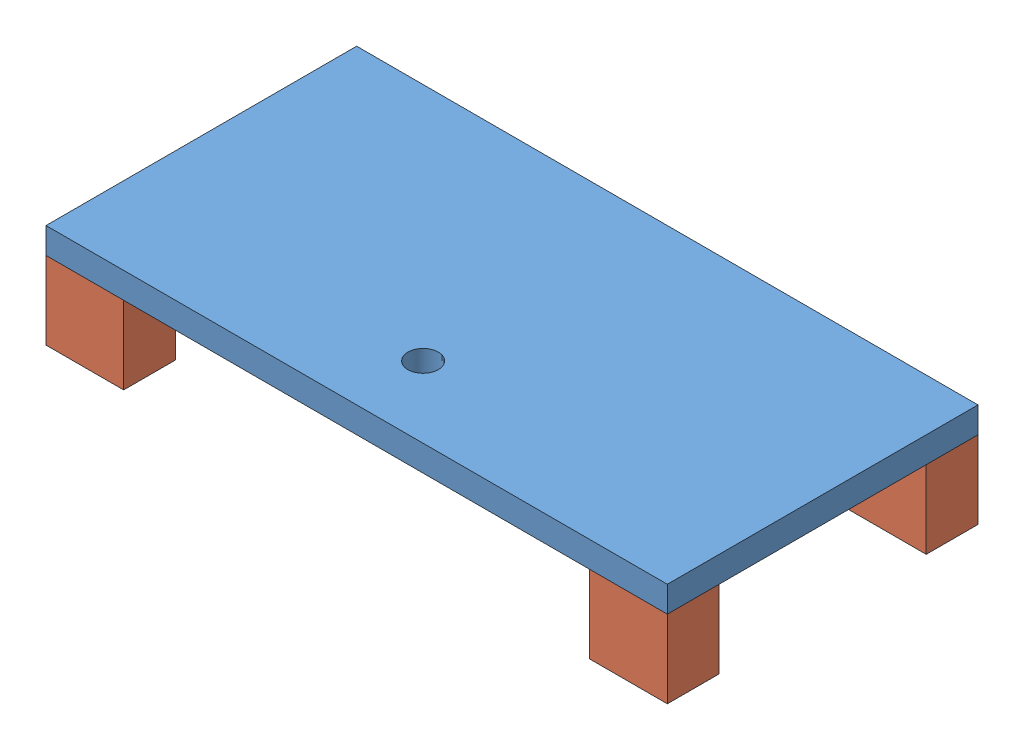
SolidWorks assembly 55model, configuration Default. Lengths in mm.
Overall size (609.6 101.6 304.8).
5 component instances, 2 part files, 12 mates.
Components (placement in the parent):
- Baseplate-1: Baseplate [Default] at (-329.9128 -7.7411 162.2827) size (609.6 25.4 304.8)
- LongSpacer-1: LongSpacer [Default] at (-329.9128 -83.9411 162.2827) size (76.2 76.2 50.8)
- LongSpacer-2: LongSpacer [Default] at (203.4872 -83.9411 162.2827) size (76.2 76.2 50.8)
- LongSpacer-3: LongSpacer [Default] at (203.4872 -83.9411 -91.7173) size (76.2 76.2 50.8)
- LongSpacer-4: LongSpacer [Default] at (-329.9128 -83.9411 -91.7173) size (76.2 76.2 50.8)
Mates (geometry in assembly coordinates):
- Coincident1: coincident aligned: plane of Baseplate-1 through (-329.9128 17.6589 162.2827) normal (0 0 1); plane of LongSpacer-1 through (-329.9128 -7.7411 162.2827) normal (0 0 1)
- Coincident3: coincident aligned: plane of Baseplate-1 through (-329.9128 17.6589 162.2827) normal (0 0 1); plane of LongSpacer-2 through (203.4872 -7.7411 162.2827) normal (0 0 1)
- Coincident4: coincident: plane of Baseplate-1 through (-329.9128 17.6589 -142.5173) normal (0 0 -1); plane of LongSpacer-3 through (265.846 -7.7411 -142.5173) normal (0 0 -1)
- Coincident5: coincident aligned: plane of Baseplate-1 through (-329.9128 17.6589 -142.5173) normal (0 0 -1); plane of LongSpacer-4 through (-329.9128 -7.7411 -142.5173) normal (0 0 -1)
- Coincident6: coincident aligned: plane of Baseplate-1 through (-329.9128 17.6589 162.2827) normal (-1 0 0); plane of LongSpacer-4 through (-329.9128 -7.7411 -91.7173) normal (-1 0 0)
- Coincident7: coincident aligned: plane of Baseplate-1 through (-329.9128 17.6589 162.2827) normal (-1 0 0); plane of LongSpacer-1 through (-329.9128 -7.7411 162.2827) normal (-1 0 0)
- Coincident8: coincident aligned: plane of Baseplate-1 through (279.6872 17.6589 162.2827) normal (1 0 0); plane of LongSpacer-2 through (279.6872 -7.7411 162.2827) normal (1 0 0)
- Coincident9: coincident anti-aligned: plane of Baseplate-1 through (-329.9128 -7.7411 -142.5173) normal (0 -1 0); plane of LongSpacer-1 through (-329.9128 -7.7411 111.4827) normal (0 1 0)
- Coincident10: coincident anti-aligned: plane of Baseplate-1 through (-329.9128 -7.7411 -142.5173) normal (0 -1 0); plane of LongSpacer-4 through (-329.9128 -7.7411 -142.5173) normal (0 1 0)
- Coincident11: coincident anti-aligned: plane of Baseplate-1 through (-329.9128 -7.7411 -142.5173) normal (0 -1 0); plane of LongSpacer-2 through (203.4872 -7.7411 111.4827) normal (0 1 0)
- Coincident12: coincident: plane of Baseplate-1 through (-329.9128 -7.7411 -142.5173) normal (0 -1 0); plane of LongSpacer-3 through (265.846 -7.7411 -142.5173) normal (0 1 0)
- Coincident13: coincident aligned: plane of Baseplate-1 through (279.6872 17.6589 162.2827) normal (1 0 0); plane of LongSpacer-3 through (279.6872 -7.7411 -91.7173) normal (1 0 0)
